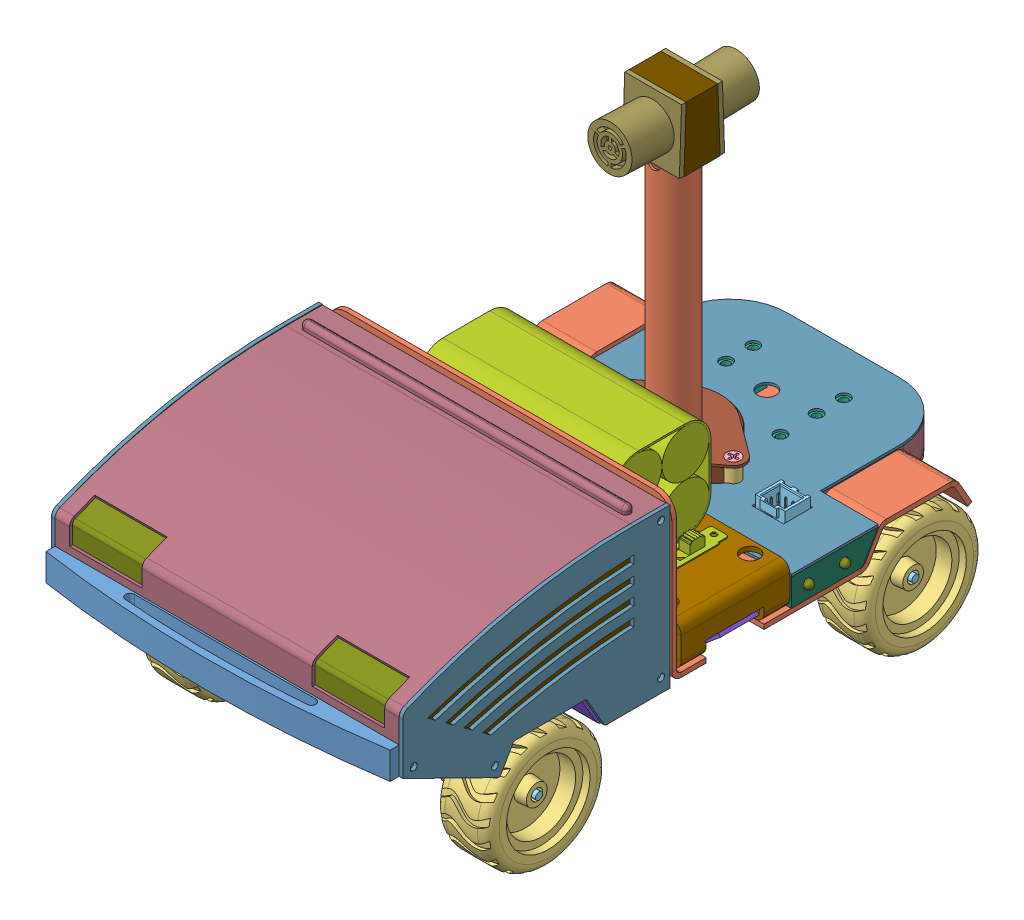
SolidWorks assembly SCOUT, TOP LEVEL, configuration Default. Lengths in mm.
Overall size (124.43 158.23 223.86).
76 component instances, 37 part files, 9 mates.
Components (placement in the parent):
- 6655k13 Thrust Washers-1: 6655k13 Thrust Washers [Default] at (-7.8856 2.7539 2.2902) size (14.15 14.15 4.9)
- REAR, TOP LEVEL-1: REAR, TOP LEVEL [Default] at (-50.0168 -33.3245 -47.0081) x (-1 0 0) z (0 0 -1) size (124.43 158.23 120.66)
  - PLATE, REAR-1: PLATE, REAR [Default] at (-42.1312 28.0774 12.7174) size (120.65 55.63 120.66)
  - WHEEL ASSEMBLY-1: WHEEL ASSEMBLY [Default-_flexible1] at (7.6153 26.9792 58.7651) x (0 0 1) z (1 0 0) size (42.46 78.6 70.03) (flexible)
    - Pololu 49x19 Wheel-1: Pololu 49x19 Wheel [Default] at (-19.8703 11.8393 2.4418) size (42.46 42.56 19)
    - Pololu Extended Micro Metal Bracket-1: Pololu Extended Micro Metal Bracket [Default] at (-19.8703 6.8393 -18.4366) size (26.6 22.49 26.04)
    - Pololu 298-1 Motor-1: Pololu 298-1 Motor [Default] at (-19.8703 11.8393 -25.1366) x (0 0 -1) z (0 1 0) size (35.87 12 10)
  - WHEEL ASSEMBLY-2: WHEEL ASSEMBLY [Default-_flexible2] at (-91.8778 26.9792 19.0244) x (0 0 -1) z (-1 0 0) size (42.46 78.6 70.03) (flexible)
    - Pololu 49x19 Wheel-1: Pololu 49x19 Wheel [Default] at (-19.8703 11.8393 2.4418) size (42.46 42.56 19)
    - Pololu Extended Micro Metal Bracket-1: Pololu Extended Micro Metal Bracket [Default] at (-19.8703 6.8393 -18.4366) size (26.6 22.49 26.04)
    - Pololu 298-1 Motor-1: Pololu 298-1 Motor [Default] at (-19.8703 11.8393 -25.1366) x (0 0 -1) z (0 1 0) size (35.87 12 10)
  - Socket Head Cap Screw_AI-1: Socket Head Cap Screw_AI [HX-SHCS 0.086-56x0.4375x0.4375-N] at (-77.6912 31.9128 47.8948) x (0 -1 0) z (-0.381305 0 -0.924449) size (13.3 3.56 3.56)
  - Socket Head Cap Screw_AI-2: Socket Head Cap Screw_AI [HX-SHCS 0.086-56x0.4375x0.4375-N] at (-77.6912 31.9128 29.8948) x (0 -1 0) z (0 0 1) size (13.3 3.56 3.56)
  - Socket Head Cap Screw_AI-3: Socket Head Cap Screw_AI [HX-SHCS 0.086-56x0.4375x0.4375-N] at (-6.5712 31.9128 29.8948) x (0 -1 0) z (0 0 1) size (13.3 3.56 3.56)
  - Socket Head Cap Screw_AI-4: Socket Head Cap Screw_AI [HX-SHCS 0.086-56x0.4375x0.4375-N] at (-6.5712 31.9128 47.8948) x (0 -1 0) z (0 0 1) size (13.3 3.56 3.56)
  - 4000mAh 7.4V Battery Pack-1: 4000mAh 7.4V Battery Pack [Default] at (-42.1312 61.2244 -25.7652) x (0 0 -1) z (1 0 0) size (34.29 34.29 68.58)
  - SENSOR, GP2Y0D810-1: SENSOR, GP2Y0D810 [Default] at (9.9271 36.6454 -23.9419) x (0 0 -1) z (0.766044 0.642788 0) size (28.32 10.54 8.89)
  - SENSOR, GP2Y0D810-2: SENSOR, GP2Y0D810 [Default] at (-94.1896 36.6454 -23.9419) x (0 0 -1) z (0.766044 -0.642788 0) size (28.32 10.54 8.89)
  - Battery Support-1: Battery Support [Default] at (-42.1312 29.7284 -26.0192) size (120.65 27.05 38.1)
  - Mounting Block-1: Mounting Block [Default] at (-42.1312 36.0784 -35.6712) x (-1 0 0) z (0 0 -1) size (25.4 12.7 25.4)
  - PF35T-48-1: PF35T-48 [Default] at (-42.1312 31.7284 12.5888) size (50 29.2 35)
  - MaxSonar EZ1-1: MaxSonar EZ1 [Default] at (-42.1312 140.4691 6.6293) x (-1 0 0) z (0 0.034899 -0.999391) size (19.94 22.1 16.38)
  - MaxSonar EZ1-2: MaxSonar EZ1 [Default] at (-42.1312 140.4691 18.5483) x (1 0 0) z (0 0.034899 0.999391) size (19.94 22.1 16.38)
  - BUMPER, REAR-1: BUMPER, REAR [Default] at (-42.1312 29.7284 53.2288) x (-1 0 0) z (0 0 -1) size (80.01 9.53 54.3)
  - PLATE, REAR COVER-1: PLATE, REAR COVER [Default] at (-42.1312 39.2534 72.2788) size (120.65 0.81 81.14)
  - MOUNTING BLOCK, COLOR SENSOR-1: MOUNTING BLOCK, COLOR SENSOR [Default] at (-97.6937 29.7284 5.6038) size (9.53 9.53 30.46)
  - MOUNTING BLOCK, COLOR SENSOR-2: MOUNTING BLOCK, COLOR SENSOR [Default] at (13.4313 29.7284 5.6038) size (9.53 9.53 30.46)
  - SENSOR, COLOR LED-1: SENSOR, COLOR LED [Default] at (-24.0807 23.782 31.9371) x (0 0 -1) z (-0.409692 -0.912224 0) size (5.83 3.66 3.66)
  - SENSOR, COLOR LED-2: SENSOR, COLOR LED [Default] at (-67.3741 22.996 31.9371) x (0 0 -1) z (-0.202984 -0.979182 0) size (5.83 3.66 3.66)
  - COPPER CONTACT-1: COPPER CONTACT [Default] at (-53.2437 34.4909 64.0238) size (15.88 6.35 4.45)
  - COPPER CONTACT-2: COPPER CONTACT [Default] at (-31.0187 34.4909 64.0238) size (15.88 6.35 4.45)
  - MOUNTING BLOCK, SONAR-1: MOUNTING BLOCK, SONAR [Default] at (-42.1312 140.3989 12.5888) x (-1 0 0) z (0 0 -1) size (19.94 22.23 12.7)
  - SHAFT, SONAR MOUNT-1: SHAFT, SONAR MOUNT [Default] at (-42.1312 52.5784 12.5888) x (-0.538443 0 0.842662) z (-0.842662 0 -0.538443) size (4.76 89.41 4.76)
  - SHAFT, SONAR SUPPORT-1: SHAFT, SONAR SUPPORT [Default] at (-42.1312 46.7284 12.5888) x (0.999987 0 0.005105) z (-0.005105 0 0.999987) size (14.22 82.87 14.22)
  - SHAFT, STEPPER SUPPORT-1: SHAFT, STEPPER SUPPORT [Default] at (-63.1312 29.6724 12.5888) size (4.76 16.26 4.76)
  - SHAFT, STEPPER SUPPORT-2: SHAFT, STEPPER SUPPORT [Default] at (-21.1312 29.6724 12.5888) x (0.987866 0 -0.155311) z (0.155311 0 0.987866) size (4.76 16.26 4.76)
  - Flat Head 100 Screw_AI-2: Flat Head 100 Screw_AI [CR-FHM1 0.112-40x0.25x0.25-N] at (-63.1312 46.7284 12.5888) x (0 -1 0) z (0 0 1) size (6.35 4.85 4.85)
  - Flat Head 100 Screw_AI-3: Flat Head 100 Screw_AI [CR-FHM1 0.112-40x0.25x0.25-N] at (-21.1312 46.7284 12.5888) x (0 -1 0) z (0 0 1) size (6.35 4.85 4.85)
  - CONNECTOR, MOLEX 6 PIN-1: CONNECTOR, MOLEX 6 PIN [Default] at (-80.2263 37.7912 12.5433) size (10.34 13.8 9.75)
  - SENSOR, COLOR LED-3: SENSOR, COLOR LED [Default] at (-64.0196 42.7147 3.5765) x (1 0 0) z (0 0.700538 -0.713616) size (5.83 3.66 3.66)
  - SENSOR, COLOR LED-4: SENSOR, COLOR LED [Default] at (-64.0196 42.7147 -9.1235) x (1 0 0) z (0 0.700538 -0.713616) size (5.83 3.66 3.66)
  - SENSOR, COLOR LED-5: SENSOR, COLOR LED [Default] at (-20.2429 42.7147 20.3311) x (-1 0 0) z (0 0.700538 0.713616) size (5.83 3.66 3.66)
  - SENSOR, COLOR LED-6: SENSOR, COLOR LED [Default] at (-20.2429 42.7147 7.6311) x (-1 0 0) z (0 0.700538 0.713616) size (5.83 3.66 3.66)
  - MOUNTING BLOCK, REAR-1: MOUNTING BLOCK, REAR [Default] at (-58.0062 34.4909 31.0038) size (9.53 9.53 28.57)
  - MOUNTING BLOCK, REAR-2: MOUNTING BLOCK, REAR [Default] at (-26.2562 34.4909 31.0038) size (9.53 9.53 28.57)
  - SW3dPS-Sliderswitch-1: SW3dPS-Sliderswitch [Standard] at (-81.1109 44.0794 -21.7288) size (7.4 16 23.2)
- FRONT, TOP LEVEL-1: FRONT, TOP LEVEL [Default] at (-84.349 -51.7544 28.3431) x (-1 0 0) z (0 0 -1) size (123.38 92.14 123.57)
  - PLATE, FRONT-1: PLATE, FRONT [Default] at (-76.4634 46.5072 -32.0242) size (120.65 12.1 60.8)
  - WHEEL ASSEMBLY-1: WHEEL ASSEMBLY [Default-_flexible3] at (-26.7168 45.4091 2.1802) x (0 0 1) z (1 0 0) size (42.46 78.6 70.03) (flexible)
    - Pololu 49x19 Wheel-1: Pololu 49x19 Wheel [Default] at (-19.8703 11.8393 2.4418) size (42.46 42.56 19)
    - Pololu Extended Micro Metal Bracket-1: Pololu Extended Micro Metal Bracket [Default] at (-19.8703 6.8393 -18.4366) size (26.6 22.49 26.04)
    - Pololu 298-1 Motor-1: Pololu 298-1 Motor [Default] at (-19.8703 11.8393 -25.1366) x (0 0 -1) z (0 1 0) size (35.87 12 10)
  - WHEEL ASSEMBLY-2: WHEEL ASSEMBLY [Default-_flexible4] at (-126.21 45.4091 -37.5605) x (0 0 -1) z (-1 0 0) size (42.46 78.6 70.03) (flexible)
    - Pololu 49x19 Wheel-1: Pololu 49x19 Wheel [Default] at (-19.8703 11.8393 2.4418) size (42.46 42.56 19)
    - Pololu Extended Micro Metal Bracket-1: Pololu Extended Micro Metal Bracket [Default] at (-19.8703 6.8393 -18.4366) size (26.6 22.49 26.04)
    - Pololu 298-1 Motor-1: Pololu 298-1 Motor [Default] at (-19.8703 11.8393 -25.1366) x (0 0 -1) z (0 1 0) size (35.87 12 10)
  - Socket Head Cap Screw_AI-1: Socket Head Cap Screw_AI [HX-SHCS 0.086-56x0.4375x0.4375-N] at (-112.0234 50.3426 -8.6902) x (0 -1 0) z (0.989468 0 0.144748) size (13.3 3.56 3.56)
  - Socket Head Cap Screw_AI-3: Socket Head Cap Screw_AI [HX-SHCS 0.086-56x0.4375x0.4375-N] at (-40.9034 50.3426 -8.6902) x (0 -1 0) z (0.700957 0 0.713204) size (13.3 3.56 3.56)
  - SENSOR, GP2Y0D810-2: SENSOR, GP2Y0D810 [Default] at (-76.7491 52.0249 -21.9932) x (1 0 0) z (0 -0.642788 0.766044) size (28.32 10.54 8.89)
  - BUMPER, FRONT-1: BUMPER, FRONT [Default] at (-76.4634 36.9822 -30.9902) x (-1 0 0) z (0 0 -1) size (69.85 9.53 6.35)
  - Mounting Block-1: Mounting Block [Default] at (-76.4634 54.5082 12.4258) size (25.4 12.7 25.4)
  - Socket Head Shoulder Screw2_AI-1: Socket Head Shoulder Screw2_AI [SHSSCREW 0.25x1.5-N] at (-76.4634 54.5082 2.5706) x (0 0 1) z (-0.728467 -0.685081 0) size (52.4 9.53 9.53)
  - Socket Head Cap Screw_AI-5: Socket Head Cap Screw_AI [HX-SHCS 0.086-56x0.4375x0.4375-N] at (-40.9034 51.2773 -26.6902) x (0 -1 0) z (-0.957829 0 -0.287339) size (13.3 3.56 3.56)
  - Socket Head Cap Screw_AI-6: Socket Head Cap Screw_AI [HX-SHCS 0.086-56x0.4375x0.4375-N] at (-112.0234 51.2773 -26.6902) x (0 -1 0) z (-0.957829 0 -0.287339) size (13.3 3.56 3.56)
  - PCB, MAIN-1: PCB, MAIN [Default] at (-76.4634 67.2082 -21.6044) size (114.3 6.68 88.9)
  - PLATE, FRONT BUMPER-1: PLATE, FRONT BUMPER [Default] at (-76.4634 48.9202 -22.7941) size (120.65 17.91 44.79)
  - COVER, FRONT-1: COVER, FRONT [Default] at (-76.4634 65.9445 25.1258) size (120.65 38.48 93.73)
  - PLATE, FRONT SIDE-1: PLATE, FRONT SIDE [Default] at (-16.1384 46.5072 25.1258) x (0 0 -1) z (1 0 0) size (93.73 55.63 1.27)
  - SW3dPS-USB_mini_B-1: SW3dPS-USB_mini_B [По умолчанию] at (-54.9865 68.8084 -58.5669) x (-1 0 0) z (0 0 -1) size (10.7 4.95 9.2)
  - HEADLIGHT COVER, FRONT-1: HEADLIGHT COVER, FRONT [Default] at (-103.1334 74.8345 -67.5842) x (-1 0 0) z (0 0 -1) size (31.75 14.4 11.68)
  - HEADLIGHT COVER, FRONT-2: HEADLIGHT COVER, FRONT [Default] at (-18.0434 74.8345 -67.5842) x (-1 0 0) z (0 0 -1) size (31.75 14.4 11.68)
  - PLATE, FRONT SIDE-2: PLATE, FRONT SIDE [Default] at (-138.0584 46.5072 25.1258) x (0 0 -1) z (1 0 0) size (93.73 55.63 1.27)
  - STRUT, FRONT SIDE-1: STRUT, FRONT SIDE [Default] at (-76.4634 98.9582 21.9508) size (120.65 3.17 6.35)
  - FILTER, FRONT COVER-1: FILTER, FRONT COVER [Default] at (-19.1356 62.8553 14.5951) x (0 0 -1) z (1 0 0) size (76.17 31.33 3)
  - FILTER, FRONT COVER-2: FILTER, FRONT COVER [Default] at (-136.7884 62.8559 13.2551) x (0 0 -1) z (1 0 0) size (76.17 31.33 3)
- BUMPER, FRONT SWITCHED-1: BUMPER, FRONT SWITCHED [Default] at (-7.8856 18.9527 98.5308) size (120.65 9.53 7.62)
Mates (geometry in assembly coordinates):
- Concentric1: concentric anti-aligned: cylinder of FRONT, TOP LEVEL-1/Socket Head Shoulder Screw2_AI-1; cylinder of 6655k13 Thrust Washers-1
- Coincident1: coincident anti-aligned: plane of 6655k13 Thrust Washers-1 through (-7.8856 2.7539 4.7413) normal (0 0 1); plane of FRONT, TOP LEVEL-1/Mounting Block-1 through (-7.8856 2.7539 4.7413) normal (0 0 -1)
- Concentric2: concentric anti-aligned: cylinder of REAR, TOP LEVEL-1/Mounting Block-1; cylinder of FRONT, TOP LEVEL-1/Socket Head Shoulder Screw2_AI-1
- Coincident2: coincident anti-aligned: plane of 6655k13 Thrust Washers-1 through (-7.8856 2.7539 -0.1609) normal (0 0 -1); plane of REAR, TOP LEVEL-1/Mounting Block-1 through (-7.8856 2.7539 -0.1609) normal (0 0 1)
- Parallel1: parallel anti-aligned: unknown of REAR, TOP LEVEL-1/PLATE, REAR-1
- Parallel2: parallel aligned: plane of REAR, TOP LEVEL-1/PLATE, REAR-1 through (52.4394 50.3789 1.3631) normal (0 1 0); plane of FRONT, TOP LEVEL-1/PCB, MAIN-1 through (-65.0356 17.0541 94.3975) normal (0 1 0)
- Coincident3: coincident anti-aligned: plane of FRONT, TOP LEVEL-1/COVER, FRONT-1 through (-68.2106 14.1902 96.9433) normal (0 0 1); plane of BUMPER, FRONT SWITCHED-1 through (-68.2106 23.7152 96.9433) normal (0 0 -1)
- Coincident4: coincident aligned: plane of FRONT, TOP LEVEL-1/COVER, FRONT-1 through (-68.2106 14.1902 96.9433) normal (0 -1 0); plane of BUMPER, FRONT SWITCHED-1 through (-7.8856 14.1902 -307.0074) normal (0 -1 0)
- Coincident5: coincident: line of FRONT, TOP LEVEL-1/PLATE, FRONT SIDE-2; plane of BUMPER, FRONT SWITCHED-1 through (52.4394 23.7152 96.9433) normal (1 0 0)
